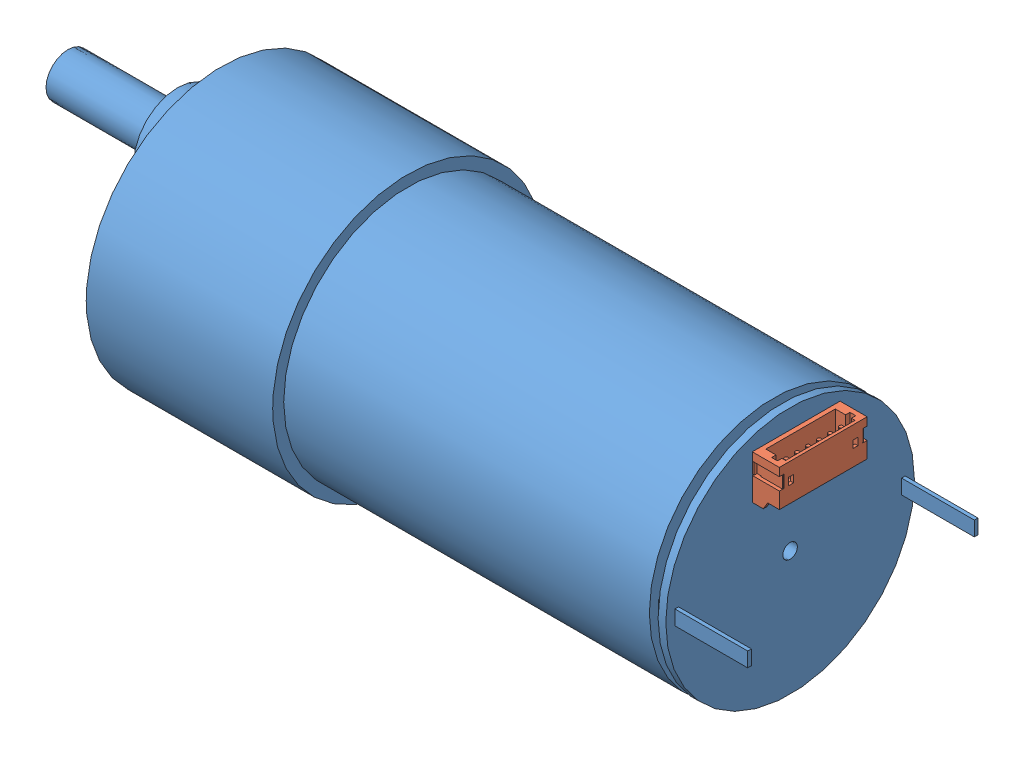
SolidWorks assembly CHR-GM37-3429K-ABHL, configuration Default. Lengths in mm.
Overall size (106.2 37 37).
2 component instances, 2 part files, 1 mates.
Components (placement in the parent):
- motor_CHR-GM37-3429K-ABHL-1: motor_CHR-GM37-3429K-ABHL [DC 12.0V 1000RMP-I10 without shaft] at origin size (106.2 37 37)
- S6B_ZR_SM4A_TF-1: S6B_ZR_SM4A_TF [Default] at (0 1.5191 -0.8356) size (3.7 6.5 12)
Mates (geometry in assembly coordinates):
- 重合/共線/共點1: coincident anti-aligned: circle of motor_CHR-GM37-3429K-ABHL-1; plane of S6B_ZR_SM4A_TF-1 through (41.25 8.3191 5.1644) normal (-1 0 0)
